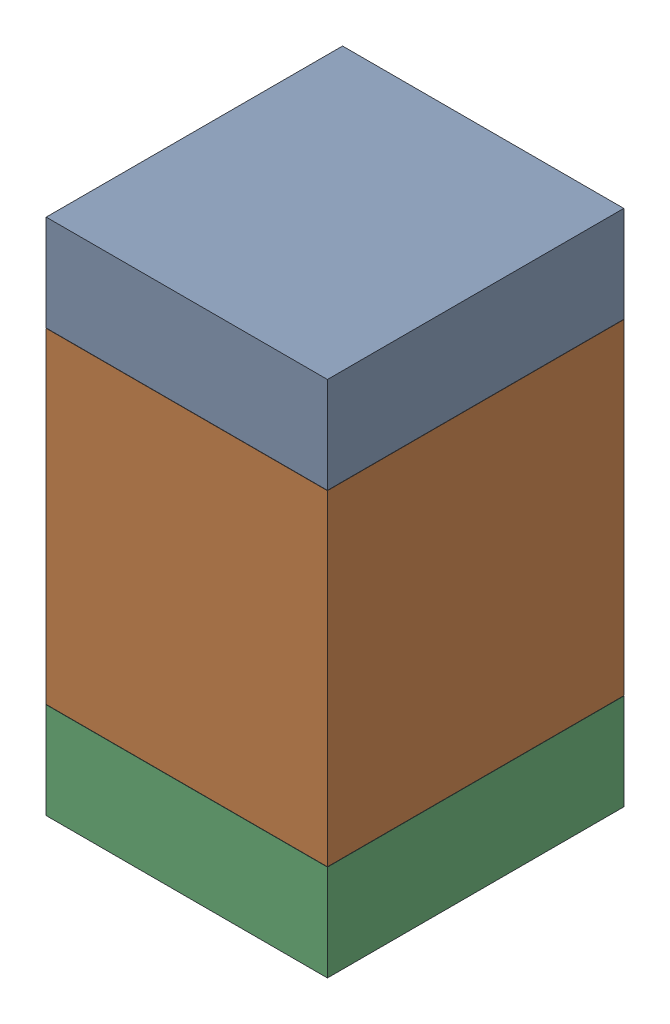
SolidWorks assembly C24, configuration Default. Lengths in mm.
Overall size (0.95 1.75 1).
6 component instances, 2 part files, 0 mates.
Components (placement in the parent):
- 6575495072-1: 6575495072 [Default] at (3.048 29.9225 0) size (0.95 0.32 1)
  - Extruded_6-1: Extruded_6 [Default] at origin size (0.95 0.32 1)
- 6575494912-1: 6575494912 [Default] at (3.048 29.21 0) size (0.95 1.1 1)
  - Extruded_7-1: Extruded_7 [Default] at origin size (0.95 1.1 1)
- 6575495072-2: 6575495072 [Default] at (3.048 28.4975 0) size (0.95 0.32 1)
  - Extruded_6-1: Extruded_6 [Default] at origin size (0.95 0.32 1)
